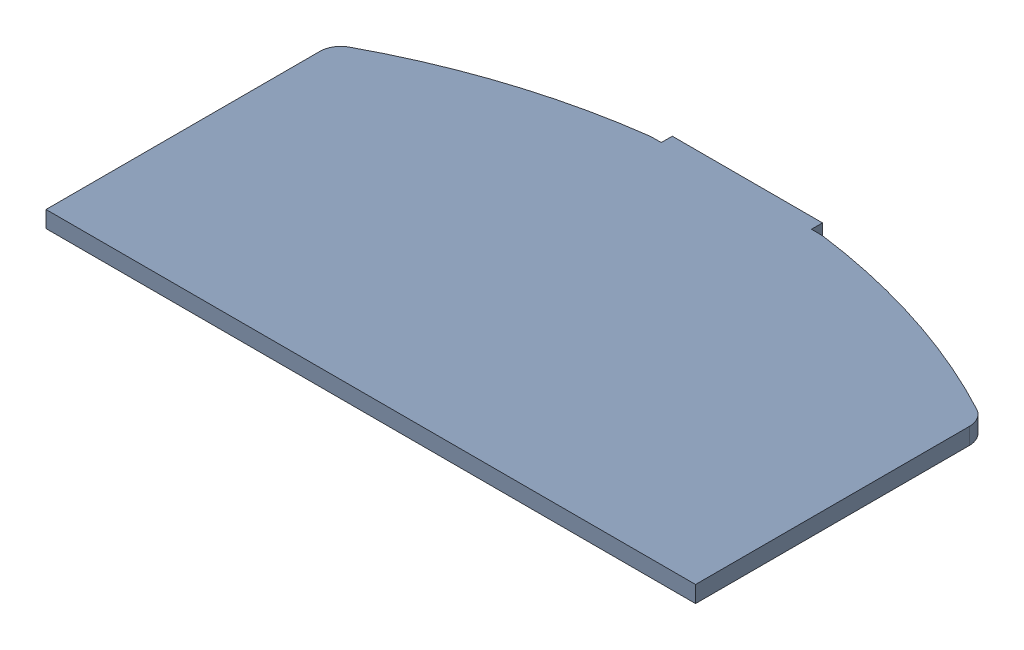
SolidWorks assembly power_pcb, configuration По умолчанию. Lengths in mm.
Overall size (58.8 4.66 34.09).
2 component instances, 2 part files, 6 mates.
Components (placement in the parent):
- power_PCB-1: power_PCB [По умолчанию] at origin size (58.8 1.5 34.09)
- 1054500101-1: 1054500101 [По умолчанию] at (0 -1.58 6.3) x (-1 0 0) z (0 -1 0) size (8.94 7.9 3.96)
Mates (geometry in assembly coordinates):
- Coincident1: coincident aligned: plane of power_PCB-1 through (6.8 1.5 1.6) normal (0 0 -1); plane of USB Type-C-1 through (-1.6243 0.7996 1.6) normal (0 0 -1)
- Coincident3: coincident aligned: plane of USB Type-C-1 through (0 -0.0004 2.08) normal (1 0 0)
- Coincident4: coincident anti-aligned: plane of power_PCB-1 through (-27.5 0 10.9094) normal (0 -1 0); plane of USB Type-C-1 through (-4.2616 0 1.6) normal (0 1 0)
- Coincident5: coincident anti-aligned: plane of 1054500101-1 through (0 3.08 6.3) normal (-1 0 0)
- Coincident6: coincident aligned: plane of power_PCB-1 through (-6.8 1.5 1.6) normal (0 0 -1); plane of 1054500101-1 through (0 3.08 1.6) normal (0 0 -1)
- Coincident8: coincident anti-aligned: plane of power_PCB-1 through (-27.5 0 10.9094) normal (0 -1 0); plane of 1054500101-1 through (-3.17 0 6.3) normal (0 1 0)
